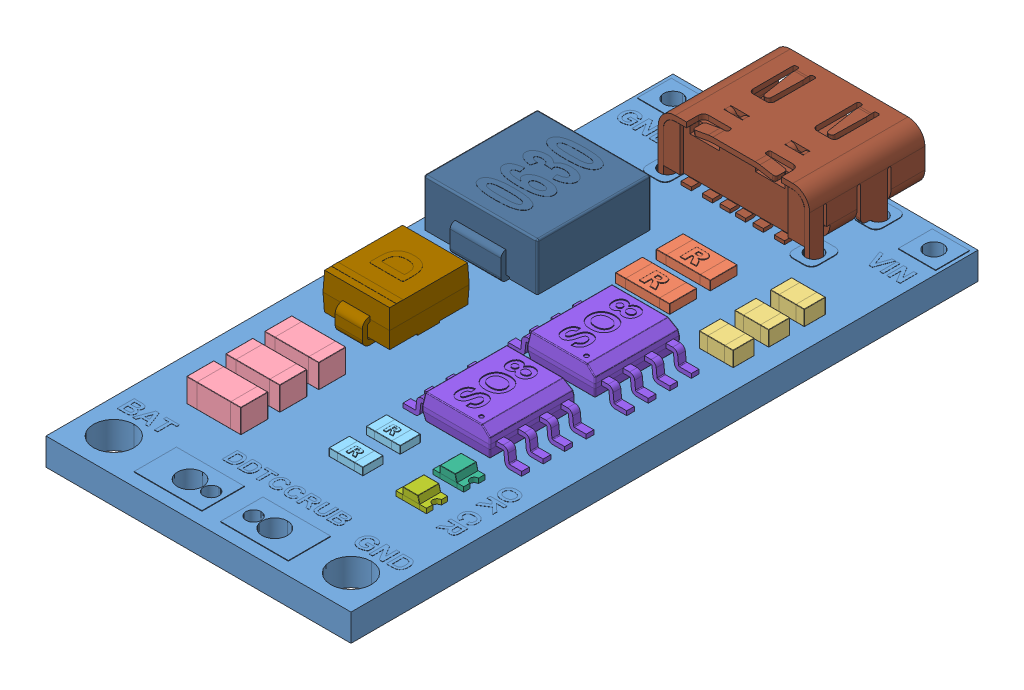
SolidWorks assembly Type_cCharger, configuration По умолчанию. Lengths in mm.
Overall size (18 4.98 38.4).
19 component instances, 11 part files, 0 mates.
Components (placement in the parent):
- DDTCCRUB CN330X.STEP-1: DDTCCRUB CN330X.STEP [По умолчанию] at origin size (18 4.98 38.4)
  - Board^DDTCCRUB CN330X.STEP-1: Board^DDTCCRUB CN330X.STEP [По умолчанию] at origin size (18 1.67 37)
  - RES_SMD_1206^DDTCCRUB CN330X.STEP-1: RES_SMD_1206^DDTCCRUB CN330X.STEP [По умолчанию] at (9 1.6 -27) size (3.2 0.59 1.6)
  - RES_SMD_1206^DDTCCRUB CN330X.STEP-2: RES_SMD_1206^DDTCCRUB CN330X.STEP [По умолчанию] at (9 1.6 -24.6) size (3.2 0.59 1.6)
  - CAP_SMD_0805_H0.9^DDTCCRUB CN330X.STEP-1: CAP_SMD_0805_H0.9^DDTCCRUB CN330X.STEP [По умолчанию] at (14.8 1.6 -27.95) size (2 0.9 1.25)
  - CAP_SMD_0805_H0.9^DDTCCRUB CN330X.STEP-2: CAP_SMD_0805_H0.9^DDTCCRUB CN330X.STEP [По умолчанию] at (14.8 1.6 -25.85) size (2 0.9 1.25)
  - CAP_SMD_0805_H0.9^DDTCCRUB CN330X.STEP-3: CAP_SMD_0805_H0.9^DDTCCRUB CN330X.STEP [По умолчанию] at (14.8 1.6 -23.75) size (2 0.9 1.25)
  - CAP_SMD_1206_H1.4^DDTCCRUB CN330X.STEP-1: CAP_SMD_1206_H1.4^DDTCCRUB CN330X.STEP [По умолчанию] at (2.5 1.6 -10.4) size (3.2 1.4 1.6)
  - CAP_SMD_1206_H1.4^DDTCCRUB CN330X.STEP-2: CAP_SMD_1206_H1.4^DDTCCRUB CN330X.STEP [По умолчанию] at (2.5 1.6 -8.1) size (3.2 1.4 1.6)
  - CAP_SMD_1206_H1.4^DDTCCRUB CN330X.STEP-3: CAP_SMD_1206_H1.4^DDTCCRUB CN330X.STEP [По умолчанию] at (2.5 1.6 -5.8) size (3.2 1.4 1.6)
  - RES_SMD_0805^DDTCCRUB CN330X.STEP-1: RES_SMD_0805^DDTCCRUB CN330X.STEP [По умолчанию] at (9.4 1.6 -9.5) size (2 0.48 1.2)
  - RES_SMD_0805^DDTCCRUB CN330X.STEP-2: RES_SMD_0805^DDTCCRUB CN330X.STEP [По умолчанию] at (9.4 1.6 -7.3) size (2 0.48 1.2)
  - LED_0805_Green^DDTCCRUB CN330X.STEP-1: LED_0805_Green^DDTCCRUB CN330X.STEP [По умолчанию] at (13.4 1.6 -9.45) size (1.8 0.68 1.25)
  - LED_0805_Red^DDTCCRUB CN330X.STEP-1: LED_0805_Red^DDTCCRUB CN330X.STEP [По умолчанию] at (13.4 1.6 -7.25) size (1.8 0.68 1.25)
  - SO8^DDTCCRUB CN330X.STEP-1: SO8^DDTCCRUB CN330X.STEP [По умолчанию] at (12.6 1.85 -11.6) size (7 1.75 5)
  - SO8^DDTCCRUB CN330X.STEP-2: SO8^DDTCCRUB CN330X.STEP [По умолчанию] at (12.6 1.85 -17.8) size (7 1.75 5)
  - Diode_DO214AA(SMB)^DDTCCRUB CN330X.STEP-1: Diode_DO214AA(SMB)^DDTCCRUB CN330X.STEP [По умолчанию] at (4.1067 1.8 -16.5533) size (3.93 2.45 5.59)
  - Inductor_SMD_AMPLF_0630^DDTCCRUB CN330X.STEP-1: Inductor_SMD_AMPLF_0630^DDTCCRUB CN330X.STEP [По умолчанию] at (4.15 1.8 -24.85) size (6.7 3.01 7.3)
  - USB_Type-C_Female_6pin^DDTCCRUB CN330X.STEP-1: USB_Type-C_Female_6pin^DDTCCRUB CN330X.STEP [По умолчанию] at (9 3.3401 -38.4) x (-1 0 0) z (0 0 -1) size (8.94 4.23 6.87)
